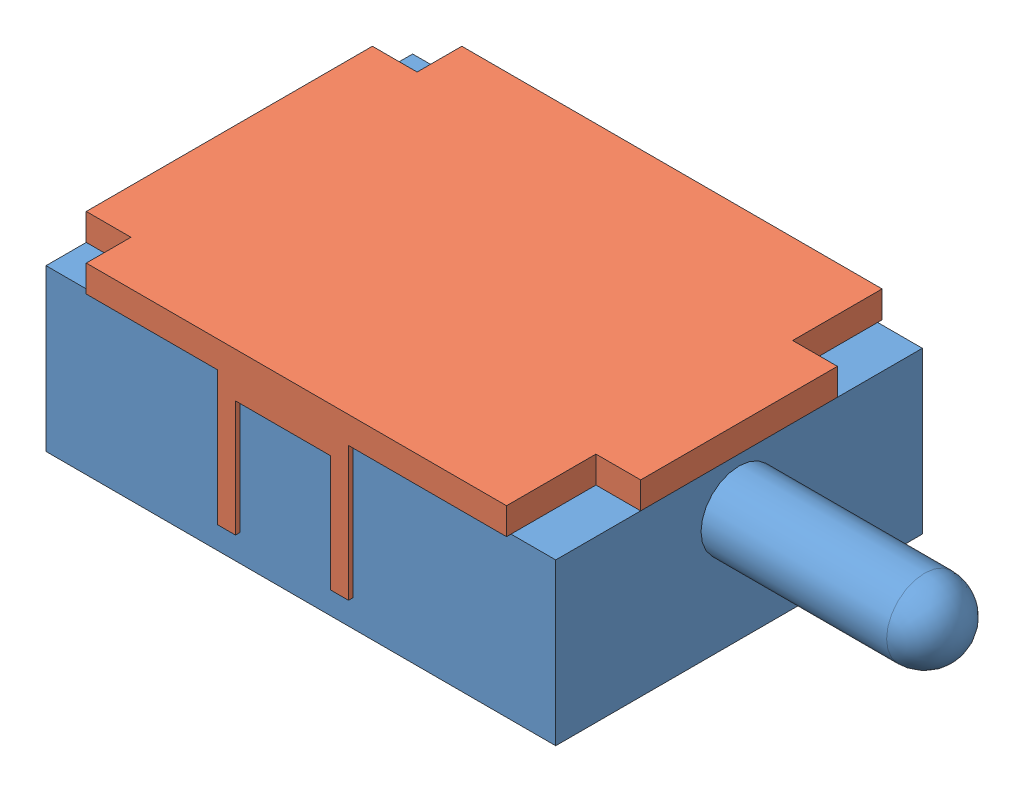
SolidWorks assembly B3_DS, configuration Default. Lengths in mm.
Overall size (8.2 2.1 4.2).
2 component instances, 2 part files, 3 mates.
Components (placement in the parent):
- DS_switch-1: DS_switch [Default] at (-0.2705 19.6227 -16.7907) size (8.2 1.8 4.1)
- DS_brace-1: DS_brace [Default] at (5.4295 19.6227 -12.5407) x (-1 0 0) z (0 0 -1) size (5.7 1.8 4.2)
Mates (geometry in assembly coordinates):
- Coincident1: coincident anti-aligned: plane of DS_switch-1 through (-0.2705 19.6227 -16.7907) normal (0 1 0); plane of DS_brace-1 through (5.4295 19.6227 -12.5407) normal (0 -1 0)
- Coincident2: coincident aligned: plane of DS_switch-1 through (-0.2705 17.8227 -16.7907) normal (-1 0 0); plane of DS_brace-1 through (-0.2705 19.9227 -13.1407) normal (-1 0 0)
- Coincident3: coincident aligned: line of DS_brace-1 through (1.6985 18.1227 -16.7907) axis (0 1 0); plane of DS_switch-1 through (-0.2705 17.8227 -16.7907) normal (0 0 -1)
